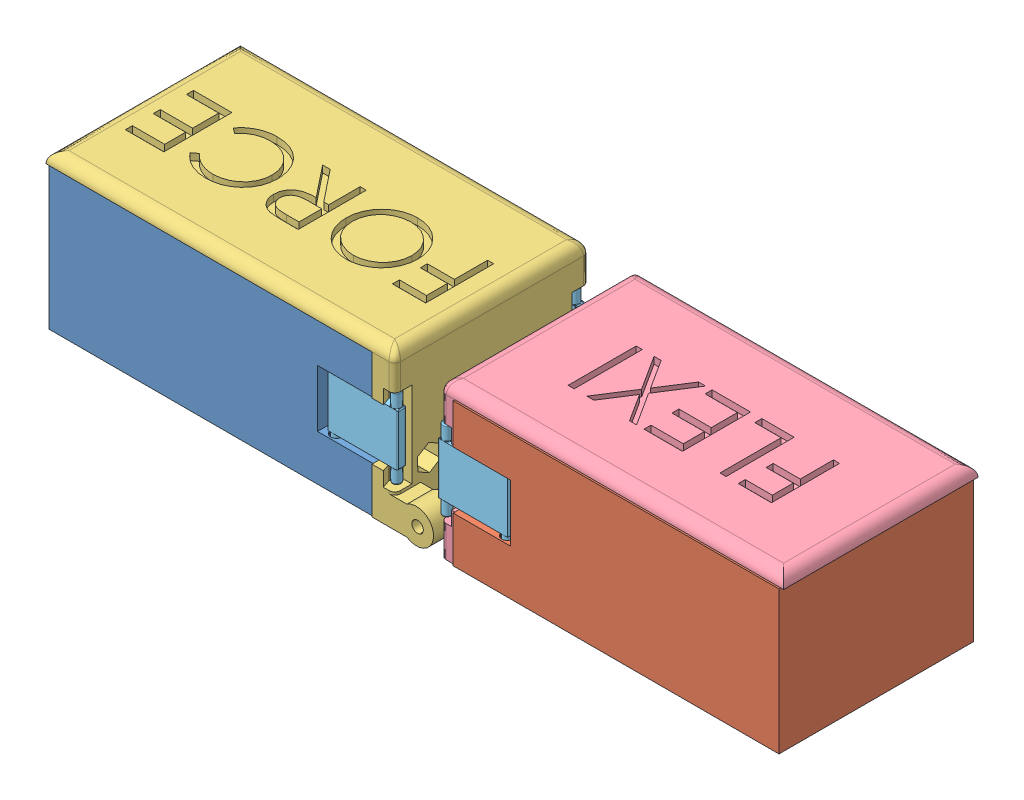
SolidWorks assembly hINGE fLEXI ASSEM, configuration Default. Lengths in mm.
Overall size (129.01 27.5 34.5).
13 component instances, 9 part files, 25 mates.
Components (placement in the parent):
- Flexi bend ard box-1: Flexi bend ard box [Default] at (-15.3009 26.0033 66.4893) size (57 25 34)
- Flexi bend bat box-1: Flexi bend bat box [Default] at (112.9089 26.0033 32.9893) x (-1 0 0) z (0 0 -1) size (57 25 34)
- Flexiforce flex lid arduino sec-1: Flexiforce flex lid arduino sec [Default] at (45.4097 53.0033 66.6893) x (-1 0 0) z (0 0 1) size (67.78 27.5 34)
- Flexiforce flex lid bat sec MK1-1: Flexiforce flex lid bat sec MK1 [Default] at (53.4097 53.0033 32.6893) x (1 0 0) z (0 0 -1) size (66.78 27.5 34)
- Box Locking Part-1: Box Locking Part [Default] at (32.7491 34.5033 33.0393) x (1 0 0) z (0 -1 0) size (12.2 1.5 14)
- Box Locking Part-2: Box Locking Part [Default] at (32.9491 34.5033 64.4393) x (1 0 0) z (0 -1 0) size (12.2 1.5 14)
- Box Locking Part-3: Box Locking Part [Default] at (64.8589 34.5033 66.4393) x (-1 0 0) z (0 -1 0) size (12.2 1.5 14)
- Box Locking Part-4: Box Locking Part [Default] at (64.6589 34.5033 35.0393) x (-1 0 0) z (0 -1 0) size (12.2 1.5 14)
- 9V-battery-1: 9V-battery [Default] at (19.9607 45.1483 29.8709) x (0 0 -1) z (0 -1 0) size (26.04 47.88 17.14)
- Arduino Nano 33 IoT-1: Arduino Nano 33 IoT [Default] at (9.4291 29.8033 49.6093) x (0 0 1) z (-1 0 0) size (17.78 5.55 45.32)
- Led RGB 5mm-1: Led RGB 5mm [Valor predeterminado] at (-1.8009 44.0033 49.4893) x (0 0.924225 0.381849) z (0 -0.381849 0.924225) size (5.6 15.8 5.8)
  - Lente^Led RGB 5mm-1: Lente^Led RGB 5mm [Valor predeterminado] at origin size (5.6 8.8 5.8) (virtual)
  - Terminais^Led RGB 5mm-1: Terminais^Led RGB 5mm [Valor predeterminado] at origin size (4.82 11.92 1.55) (virtual)
Mates (geometry in assembly coordinates):
- Coincident1: coincident anti-aligned: plane of Flexi bend ard box-1 through (-15.3009 51.0033 66.4893) normal (0 1 0); plane of Flexiforce flex lid arduino sec-1 through (45.4097 51.0033 66.6893) normal (0 -1 0)
- Coincident2: coincident anti-aligned: plane of Flexi bend ard box-1 through (-13.3009 51.0033 63.4893) normal (0 0 -1); plane of Flexiforce flex lid arduino sec-1 through (-8.5903 51.0033 63.4893) normal (0 0 1)
- Coincident3: coincident anti-aligned: plane of Flexi bend bat box-1 through (112.9089 51.0033 32.9893) normal (0 1 0); plane of Flexiforce flex lid bat sec MK1-1 through (53.4097 51.0033 32.6893) normal (0 -1 0)
- Coincident4: coincident anti-aligned: plane of Flexi bend bat box-1 through (106.9089 50.0033 33.9893) normal (0 0 1); plane of Flexiforce flex lid bat sec MK1-1 through (105.4097 48.3033 33.9893) normal (0 0 -1)
- Concentric1: concentric anti-aligned: cylinder of Flexiforce flex lid arduino sec-1 through (49.4097 28.5033 33.6893) axis (0 0 1) radius 1; cylinder of Flexiforce flex lid bat sec MK1-1 through (49.4097 28.5033 60.6893) axis (0 0 -1) radius 1
- Concentric2: concentric anti-aligned: cylinder of Flexi bend ard box-1 through (33.4991 31.5033 33.7893) axis (0 1 0) radius 1; cylinder of Box Locking Part-1 through (33.4991 45.5033 33.7893) axis (0 -1 0) radius 0.75
- Distance1: distance = 0.5 mm anti-aligned: plane of Box Locking Part-1 through (32.7491 43.5033 34.5393) normal (0 1 0); plane of Flexi bend ard box-1 through (41.6991 44.0033 34.9893) normal (0 -1 0)
- Concentric3: concentric anti-aligned: cylinder of Flexi bend bat box-1 through (63.9089 31.5033 34.2893) axis (0 1 0) radius 1; cylinder of Box Locking Part-4 through (63.9089 45.5033 34.2893) axis (0 -1 0) radius 0.75
- Distance2: distance = 0.5 mm anti-aligned: plane of Box Locking Part-4 through (64.6589 34.5033 33.5393) normal (0 -1 0); plane of Flexi bend bat box-1 through (55.9089 34.0033 35.4893) normal (0 1 0)
- Concentric4: concentric anti-aligned: cylinder of Flexi bend ard box-1 through (33.6991 31.5033 65.1893) axis (0 1 0) radius 1; cylinder of Box Locking Part-2 through (33.6991 45.5033 65.1893) axis (0 -1 0) radius 0.75
- Distance3: distance = 0.5 mm anti-aligned: plane of Box Locking Part-2 through (32.9491 34.5033 65.9393) normal (0 -1 0); plane of Flexi bend ard box-1 through (41.6991 34.0033 63.9893) normal (0 1 0)
- Concentric5: concentric anti-aligned: cylinder of Flexi bend bat box-1 through (64.1089 31.5033 65.6893) axis (0 1 0) radius 1; cylinder of Box Locking Part-3 through (64.1089 45.5033 65.6893) axis (0 -1 0) radius 0.75
- Distance4: distance = 0.5 mm anti-aligned: plane of Box Locking Part-3 through (64.8589 34.5033 64.9393) normal (0 -1 0); plane of Flexi bend bat box-1 through (55.9089 34.0033 64.4893) normal (0 1 0)
- Distance5: distance = 0.75 mm anti-aligned: plane of Flexiforce flex lid bat sec MK1-1 through (53.4097 23.0033 37.9393) normal (0 0 -1); plane of Flexiforce flex lid arduino sec-1 through (45.4097 23.0033 37.1893) normal (0 0 1)
- Parallel1: parallel aligned: plane of Flexi bend bat box-1 through (112.9089 51.0033 66.9893) normal (0 0 1); plane of Flexiforce flex lid arduino sec-1 through (45.4097 51.0033 66.6893) normal (0 0 1)
- Coincident5: coincident anti-aligned: plane of Flexi bend bat box-1 through (112.9089 28.0033 32.9893) normal (0 1 0); plane of 9V-battery-1 through (88.4209 28.0033 49.9718) normal (0 -1 0)
- Distance6: distance = 2 mm anti-aligned: plane of 9V-battery-1 through (108.9089 28.7653 61.4653) normal (1 0 0); plane of Flexi bend bat box-1 through (110.9089 51.0033 35.9893) normal (-1 0 0)
- Distance7: distance = 1 mm anti-aligned: plane of 9V-battery-1 through (88.4209 36.3983 62.9893) normal (0 0 1); plane of Flexi bend bat box-1 through (110.9089 51.0033 63.9893) normal (0 0 -1)
- Concentric6: concentric aligned: cylinder of Flexi bend ard box-1 through (-11.3009 3.0033 41.9893) axis (0 1 0) radius 0.9; cylinder of Arduino Nano 33 IoT-1 through (-11.3009 -16.8802 41.9893) axis (0 1 0) radius 0.8
- Distance8: distance = 1 mm anti-aligned: plane of Flexi bend ard box-1 through (-15.3009 28.0033 66.4893) normal (0 1 0); plane of Arduino Nano 33 IoT-1 through (9.4291 29.0033 49.6093) normal (0 -1 0)
- Angle1: planar angle = 0 rad anti-aligned: plane of Arduino Nano 33 IoT-1 through (31.4291 29.8033 40.7193) normal (0 0 -1); plane of Flexi bend ard box-1 through (-13.3009 51.0033 35.4893) normal (0 0 1)
- Concentric7: concentric anti-aligned: cone of Flexi bend ard box-1 through (-15.3009 44.0033 49.4893) axis (-1 0 0); cylinder of Led RGB 5mm-1/Lente^Led RGB 5mm-1 through (-15.6009 44.0033 49.4893) axis (1 0 0) radius 2.5
- Concentric8: concentric anti-aligned: circle of Flexi bend ard box-1; circle of Led RGB 5mm-1/Lente^Led RGB 5mm-1
- Coincident10: coincident anti-aligned: plane of Flexi bend ard box-1 through (-7.8009 44.0033 49.4893) normal (1 0 0); plane of Led RGB 5mm-1/Lente^Led RGB 5mm-1 through (-7.8009 44.0033 49.4893) normal (-1 0 0)
- Angle2: planar angle = 3.141593 rad anti-aligned: plane of Flexi bend bat box-1 through (112.9089 26.0033 32.9893) normal (0 -1 0); plane of Flexi bend ard box-1 through (-15.3009 26.0033 66.4893) normal (0 -1 0)
